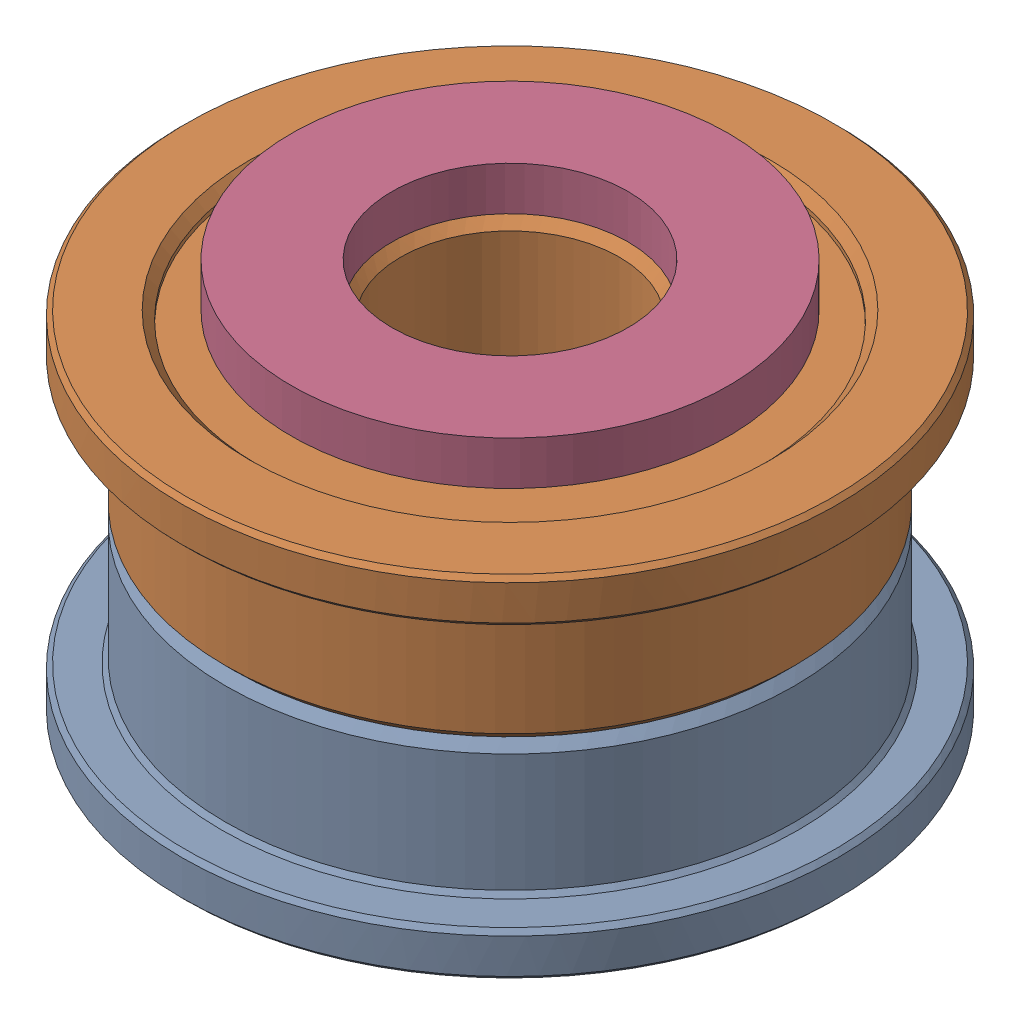
SolidWorks assembly Idler Pulley Assembly v3_1, configuration Default. Lengths in mm.
Overall size (15 10 15).
4 component instances, 3 part files, 0 mates.
Components (placement in the parent):
- F695-2RS v1 (1)-1: F695-2RS v1 (1) [Default] at origin size (15 4 15)
- F695-2RS v1 (2)-1: F695-2RS v1 (2) [Default] at (0 8 0) x (-1 0 0) z (0 0 1) size (15 4 15)
- M5 1mm Spacer-1: M5 1mm Spacer [Default] at (0 0 -350) size (10 1 10)
- M5 1mm Spacer-2: M5 1mm Spacer [Default] at (0 9 -350) size (10 1 10)
